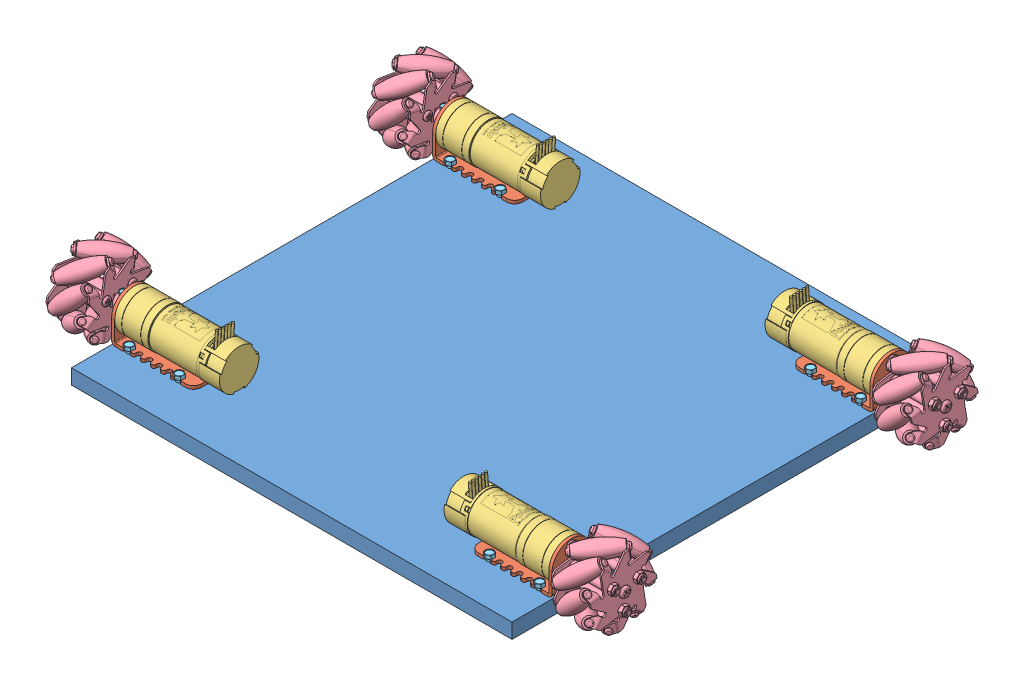
SolidWorks assembly Motor_Wheel_Assembly2, configuration Default. Lengths in mm.
Overall size (353.35 66.93 279.4).
37 component instances, 5 part files, 44 mates.
Components (placement in the parent):
- motor_Mount_plate-1: motor_Mount_plate [Default] at (148.2715 106.099 214.9972) size (279.4 9.53 279.4)
- Motor_Wheel_Assembly-1: Motor_Wheel_Assembly [Default] at (61.3699 101.7509 295.5817) x (0 0 1) z (-1 0 0) size (66.93 66.93 105.45)
  - pololu-25d-mm-metal-gearmotor-bracket.step-1: pololu-25d-mm-metal-gearmotor-bracket.step [Default] at (22.2155 27.3731 38.2734) size (25 27 52)
  - 25d-metal-gearmotor-34-47-encoder.step-1: 25d-metal-gearmotor-34-47-encoder.step [Default] at (21.2155 28.3731 50.7734) size (25 30.75 78.95)
  - 48MM Steel Mecanum Wheel2-1: 48MM Steel Mecanum Wheel2 [Default] at (-15.358 23.7538 36.4991) x (0 0 1) z (0.578972 0.815347 0) size (35.5 48 48)
  - hex screw_am-1: hex screw_am [B18.6.7M - M2.5 x 0.45 x 3 Indented HHMS --3N] at (21.4481 34.8545 57.659) x (-0.070518 -0.997511 -0.000043) z (-0.2808 0.019809 0.959562) size (5.1 4.62 4)
- Motor_Wheel_Assembly-2: Motor_Wheel_Assembly [Default] at (61.3699 101.7509 91.9817) x (0 0 1) z (-1 0 0) size (66.93 66.93 105.45)
  - pololu-25d-mm-metal-gearmotor-bracket.step-1: pololu-25d-mm-metal-gearmotor-bracket.step [Default] at (22.2155 27.3731 38.2734) size (25 27 52)
  - 25d-metal-gearmotor-34-47-encoder.step-1: 25d-metal-gearmotor-34-47-encoder.step [Default] at (21.2155 28.3731 50.7734) size (25 30.75 78.95)
  - 48MM Steel Mecanum Wheel2-1: 48MM Steel Mecanum Wheel2 [Default] at (-15.358 23.7538 36.4991) x (0 0 1) z (0.578972 0.815347 0) size (35.5 48 48)
  - hex screw_am-1: hex screw_am [B18.6.7M - M2.5 x 0.45 x 3 Indented HHMS --3N] at (21.4481 34.8545 57.659) x (-0.070518 -0.997511 -0.000043) z (-0.2808 0.019809 0.959562) size (5.1 4.62 4)
- Motor_Wheel_Assembly-3: Motor_Wheel_Assembly [Default] at (235.1732 101.7509 134.4127) x (0 0 -1) z (1 0 0) size (66.93 66.93 105.45)
  - pololu-25d-mm-metal-gearmotor-bracket.step-1: pololu-25d-mm-metal-gearmotor-bracket.step [Default] at (22.2155 27.3731 38.2734) size (25 27 52)
  - 25d-metal-gearmotor-34-47-encoder.step-1: 25d-metal-gearmotor-34-47-encoder.step [Default] at (21.2155 28.3731 50.7734) size (25 30.75 78.95)
  - 48MM Steel Mecanum Wheel2-1: 48MM Steel Mecanum Wheel2 [Default] at (-15.358 23.7538 36.4991) x (0 0 1) z (0.578972 0.815347 0) size (35.5 48 48)
  - hex screw_am-1: hex screw_am [B18.6.7M - M2.5 x 0.45 x 3 Indented HHMS --3N] at (21.4481 34.8545 57.659) x (-0.070518 -0.997511 -0.000043) z (-0.2808 0.019809 0.959562) size (5.1 4.62 4)
- Motor_Wheel_Assembly-4: Motor_Wheel_Assembly [Default] at (235.1732 101.7509 338.0127) x (0 0 -1) z (1 0 0) size (66.93 66.93 105.45)
  - pololu-25d-mm-metal-gearmotor-bracket.step-1: pololu-25d-mm-metal-gearmotor-bracket.step [Default] at (22.2155 27.3731 38.2734) size (25 27 52)
  - 25d-metal-gearmotor-34-47-encoder.step-1: 25d-metal-gearmotor-34-47-encoder.step [Default] at (21.2155 28.3731 50.7734) size (25 30.75 78.95)
  - 48MM Steel Mecanum Wheel2-1: 48MM Steel Mecanum Wheel2 [Default] at (-15.358 23.7538 36.4991) x (0 0 1) z (0.578972 0.815347 0) size (35.5 48 48)
  - hex screw_am-1: hex screw_am [B18.6.7M - M2.5 x 0.45 x 3 Indented HHMS --3N] at (21.4481 34.8545 57.659) x (-0.070518 -0.997511 -0.000043) z (-0.2808 0.019809 0.959562) size (5.1 4.62 4)
- hex screw_am-2: hex screw_am [B18.6.7M - M3 x 0.5 x 8 Indented HHMS --8N] at (278.4215 119.924 327.6472) x (0 -1 0) z (-0.546944 0 0.837169) size (10.3 5.77 5)
- hex screw_am-3: hex screw_am [B18.6.7M - M3 x 0.5 x 8 Indented HHMS --8N] at (18.1215 119.924 327.6472) x (0 -1 0) z (-0.546944 0 0.837169) size (10.3 5.77 5)
- hex screw_am-4: hex screw_am [B18.6.7M - M3 x 0.5 x 8 Indented HHMS --8N] at (18.1215 119.924 305.9472) x (0 -1 0) z (-0.546944 0 0.837169) size (10.3 5.77 5)
- hex screw_am-5: hex screw_am [B18.6.7M - M3 x 0.5 x 8 Indented HHMS --8N] at (49.8515 119.924 305.9472) x (0 -1 0) z (-0.546944 0 0.837169) size (10.3 5.77 5)
- hex screw_am-6: hex screw_am [B18.6.7M - M3 x 0.5 x 8 Indented HHMS --8N] at (18.1215 119.924 102.3472) x (0 -1 0) z (-0.546944 0 0.837169) size (10.3 5.77 5)
- hex screw_am-7: hex screw_am [B18.6.7M - M3 x 0.5 x 8 Indented HHMS --8N] at (18.1215 119.924 124.0472) x (0 -1 0) z (-0.546944 0 0.837169) size (10.3 5.77 5)
- hex screw_am-8: hex screw_am [B18.6.7M - M3 x 0.5 x 8 Indented HHMS --8N] at (49.8515 119.924 124.0472) x (0 -1 0) z (-0.546944 0 0.837169) size (10.3 5.77 5)
- hex screw_am-9: hex screw_am [B18.6.7M - M3 x 0.5 x 8 Indented HHMS --8N] at (278.4215 119.924 305.9472) x (0 -1 0) z (0 0 1) size (10.3 5.77 5)
- hex screw_am-10: hex screw_am [B18.6.7M - M3 x 0.5 x 8 Indented HHMS --8N] at (49.8515 119.924 327.6472) x (0 -1 0) z (-0.546944 0 0.837169) size (10.3 5.77 5)
- hex screw_am-11: hex screw_am [B18.6.7M - M3 x 0.5 x 8 Indented HHMS --8N] at (246.6915 119.924 327.6472) x (0 -1 0) z (-0.546944 0 0.837169) size (10.3 5.77 5)
- hex screw_am-12: hex screw_am [B18.6.7M - M3 x 0.5 x 8 Indented HHMS --8N] at (246.6915 119.924 305.9472) x (0 -1 0) z (-0.546944 0 0.837169) size (10.3 5.77 5)
- hex screw_am-13: hex screw_am [B18.6.7M - M3 x 0.5 x 8 Indented HHMS --8N] at (49.8515 119.924 102.3472) x (0 -1 0) z (-0.546944 0 0.837169) size (10.3 5.77 5)
- hex screw_am-14: hex screw_am [B18.6.7M - M3 x 0.5 x 8 Indented HHMS --8N] at (278.4215 119.924 102.3472) x (0 -1 0) z (-0.546944 0 0.837169) size (10.3 5.77 5)
- hex screw_am-15: hex screw_am [B18.6.7M - M3 x 0.5 x 8 Indented HHMS --8N] at (246.6915 119.924 124.0472) x (0 -1 0) z (-0.546944 0 0.837169) size (10.3 5.77 5)
- hex screw_am-16: hex screw_am [B18.6.7M - M3 x 0.5 x 8 Indented HHMS --8N] at (246.6915 119.924 102.3472) x (0 -1 0) z (-0.546944 0 0.837169) size (10.3 5.77 5)
- hex screw_am-17: hex screw_am [B18.6.7M - M3 x 0.5 x 8 Indented HHMS --8N] at (278.4215 119.924 124.0472) x (0 -1 0) z (-0.546944 0 0.837169) size (10.3 5.77 5)
Mates (geometry in assembly coordinates):
- Coincident1: coincident anti-aligned: plane of motor_Mount_plate-1 through (148.2715 115.624 214.9972) normal (0 1 0); plane of Motor_Wheel_Assembly-4/pololu-25d-mm-metal-gearmotor-bracket.step-1 through (285.9465 115.624 304.2972) normal (0 -1 0)
- Concentric1: concentric aligned: cylinder of motor_Mount_plate-1 through (278.4215 115.624 305.9472) axis (0 1 0) radius 1.65; cylinder of Motor_Wheel_Assembly-4/pololu-25d-mm-metal-gearmotor-bracket.step-1 through (278.4215 115.624 305.9472) axis (0 1 0) radius 1.65
- Parallel1: parallel aligned: plane of motor_Mount_plate-1 through (287.9715 115.624 75.2972) normal (1 0 0); plane of Motor_Wheel_Assembly-4/pololu-25d-mm-metal-gearmotor-bracket.step-1 through (287.9465 117.624 304.2972) normal (1 0 0)
- Coincident3: coincident anti-aligned: plane of motor_Mount_plate-1 through (148.2715 115.624 214.9972) normal (0 1 0); plane of Motor_Wheel_Assembly-3/pololu-25d-mm-metal-gearmotor-bracket.step-1 through (285.9465 115.624 100.6972) normal (0 -1 0)
- Concentric2: concentric aligned: cylinder of motor_Mount_plate-1 through (278.4215 115.624 102.3472) axis (0 1 0) radius 1.65; cylinder of Motor_Wheel_Assembly-3/pololu-25d-mm-metal-gearmotor-bracket.step-1 through (278.4215 115.624 102.3472) axis (0 1 0) radius 1.65
- Parallel3: parallel aligned: plane of motor_Mount_plate-1 through (287.9715 115.624 75.2972) normal (1 0 0); plane of Motor_Wheel_Assembly-3/pololu-25d-mm-metal-gearmotor-bracket.step-1 through (287.9465 117.624 100.6972) normal (1 0 0)
- Coincident6: coincident anti-aligned: plane of motor_Mount_plate-1 through (148.2715 115.624 214.9972) normal (0 1 0); plane of Motor_Wheel_Assembly-2/pololu-25d-mm-metal-gearmotor-bracket.step-1 through (10.5965 115.624 125.6972) normal (0 -1 0)
- Concentric3: concentric aligned: cylinder of motor_Mount_plate-1 through (18.1215 115.624 124.0472) axis (0 1 0) radius 1.65; cylinder of Motor_Wheel_Assembly-2/pololu-25d-mm-metal-gearmotor-bracket.step-1 through (18.1215 115.624 124.0472) axis (0 1 0) radius 1.65
- Parallel4: parallel aligned: plane of motor_Mount_plate-1 through (8.5715 115.624 75.2972) normal (-1 0 0); plane of Motor_Wheel_Assembly-2/pololu-25d-mm-metal-gearmotor-bracket.step-1 through (8.5965 117.624 125.6972) normal (-1 0 0)
- Coincident8: coincident anti-aligned: plane of motor_Mount_plate-1 through (148.2715 115.624 214.9972) normal (0 1 0); plane of Motor_Wheel_Assembly-1/pololu-25d-mm-metal-gearmotor-bracket.step-1 through (10.5965 115.624 329.2972) normal (0 -1 0)
- Concentric4: concentric aligned: cylinder of motor_Mount_plate-1 through (18.1215 115.624 305.9472) axis (0 1 0) radius 1.65; cylinder of Motor_Wheel_Assembly-1/pololu-25d-mm-metal-gearmotor-bracket.step-1 through (18.1215 115.624 305.9472) axis (0 1 0) radius 1.65
- Parallel5: parallel aligned: plane of motor_Mount_plate-1 through (8.5715 115.624 75.2972) normal (-1 0 0); plane of Motor_Wheel_Assembly-1/pololu-25d-mm-metal-gearmotor-bracket.step-1 through (8.5965 117.624 329.2972) normal (-1 0 0)
- Concentric6: concentric aligned: cylinder of motor_Mount_plate-1 through (18.1215 115.624 327.6472) axis (0 1 0) radius 1.65; cylinder of hex screw_am-3 through (18.1215 145.324 327.6472) axis (0 1 0) radius 1.5
- Coincident9: coincident anti-aligned: plane of Motor_Wheel_Assembly-1/pololu-25d-mm-metal-gearmotor-bracket.step-1 through (10.5965 117.624 329.2972) normal (0 1 0); plane of hex screw_am-3 through (19.3773 117.624 328.4676) normal (0 -1 0)
- Concentric7: concentric aligned: cylinder of motor_Mount_plate-1 through (49.8515 115.624 327.6472) axis (0 1 0) radius 1.65; cylinder of hex screw_am-10 through (49.8515 145.324 327.6472) axis (0 1 0) radius 1.5
- Coincident10: coincident anti-aligned: plane of Motor_Wheel_Assembly-1/pololu-25d-mm-metal-gearmotor-bracket.step-1 through (10.5965 117.624 329.2972) normal (0 1 0); plane of hex screw_am-10 through (51.1073 117.624 328.4676) normal (0 -1 0)
- Concentric8: concentric aligned: cylinder of motor_Mount_plate-1 through (246.6915 115.624 327.6472) axis (0 1 0) radius 1.65; cylinder of hex screw_am-11 through (246.6915 145.324 327.6472) axis (0 1 0) radius 1.5
- Coincident11: coincident anti-aligned: plane of Motor_Wheel_Assembly-4/pololu-25d-mm-metal-gearmotor-bracket.step-1 through (285.9465 117.624 304.2972) normal (0 1 0); plane of hex screw_am-11 through (247.9473 117.624 328.4676) normal (0 -1 0)
- Concentric9: concentric aligned: cylinder of motor_Mount_plate-1 through (278.4215 115.624 327.6472) axis (0 1 0) radius 1.65; cylinder of hex screw_am-2 through (278.4215 145.324 327.6472) axis (0 1 0) radius 1.5
- Coincident12: coincident anti-aligned: plane of Motor_Wheel_Assembly-4/pololu-25d-mm-metal-gearmotor-bracket.step-1 through (285.9465 117.624 304.2972) normal (0 1 0); plane of hex screw_am-2 through (279.6773 117.624 328.4676) normal (0 -1 0)
- Concentric10: concentric aligned: cylinder of motor_Mount_plate-1 through (246.6915 115.624 305.9472) axis (0 1 0) radius 1.65; cylinder of hex screw_am-12 through (246.6915 145.324 305.9472) axis (0 1 0) radius 1.5
- Coincident13: coincident anti-aligned: plane of Motor_Wheel_Assembly-4/pololu-25d-mm-metal-gearmotor-bracket.step-1 through (285.9465 117.624 304.2972) normal (0 1 0); plane of hex screw_am-12 through (247.9473 117.624 306.7676) normal (0 -1 0)
- Coincident14: coincident anti-aligned: plane of Motor_Wheel_Assembly-4/pololu-25d-mm-metal-gearmotor-bracket.step-1 through (285.9465 117.624 304.2972) normal (0 1 0); plane of hex screw_am-9 through (279.9215 117.624 305.9472) normal (0 -1 0)
- Concentric11: concentric aligned: cylinder of motor_Mount_plate-1 through (278.4215 115.624 305.9472) axis (0 1 0) radius 1.65; cylinder of hex screw_am-9 through (278.4215 145.324 305.9472) axis (0 1 0) radius 1.5
- Concentric12: concentric aligned: cylinder of motor_Mount_plate-1 through (278.4215 115.624 102.3472) axis (0 1 0) radius 1.65; cylinder of hex screw_am-14 through (278.4215 145.324 102.3472) axis (0 1 0) radius 1.5
- Coincident15: coincident anti-aligned: plane of Motor_Wheel_Assembly-3/pololu-25d-mm-metal-gearmotor-bracket.step-1 through (285.9465 117.624 100.6972) normal (0 1 0); plane of hex screw_am-14 through (279.6773 117.624 103.1676) normal (0 -1 0)
- Concentric13: concentric aligned: cylinder of motor_Mount_plate-1 through (246.6915 115.624 102.3472) axis (0 1 0) radius 1.65; cylinder of hex screw_am-16 through (246.6915 145.324 102.3472) axis (0 1 0) radius 1.5
- Coincident16: coincident anti-aligned: plane of Motor_Wheel_Assembly-3/pololu-25d-mm-metal-gearmotor-bracket.step-1 through (285.9465 117.624 100.6972) normal (0 1 0); plane of hex screw_am-16 through (247.9473 117.624 103.1676) normal (0 -1 0)
- Concentric14: concentric aligned: cylinder of motor_Mount_plate-1 through (49.8515 115.624 102.3472) axis (0 1 0) radius 1.65; cylinder of hex screw_am-13 through (49.8515 145.324 102.3472) axis (0 1 0) radius 1.5
- Coincident17: coincident anti-aligned: plane of Motor_Wheel_Assembly-2/pololu-25d-mm-metal-gearmotor-bracket.step-1 through (10.5965 117.624 125.6972) normal (0 1 0); plane of hex screw_am-13 through (51.1073 117.624 103.1676) normal (0 -1 0)
- Concentric15: concentric aligned: cylinder of motor_Mount_plate-1 through (18.1215 115.624 102.3472) axis (0 1 0) radius 1.65; cylinder of hex screw_am-6 through (18.1215 145.324 102.3472) axis (0 1 0) radius 1.5
- Coincident18: coincident anti-aligned: plane of Motor_Wheel_Assembly-2/pololu-25d-mm-metal-gearmotor-bracket.step-1 through (10.5965 117.624 125.6972) normal (0 1 0); plane of hex screw_am-6 through (19.3773 117.624 103.1676) normal (0 -1 0)
- Concentric16: concentric aligned: cylinder of motor_Mount_plate-1 through (18.1215 115.624 124.0472) axis (0 1 0) radius 1.65; cylinder of hex screw_am-7 through (18.1215 145.324 124.0472) axis (0 1 0) radius 1.5
- Coincident19: coincident anti-aligned: plane of Motor_Wheel_Assembly-2/pololu-25d-mm-metal-gearmotor-bracket.step-1 through (10.5965 117.624 125.6972) normal (0 1 0); plane of hex screw_am-7 through (19.3773 117.624 124.8676) normal (0 -1 0)
- Concentric17: concentric aligned: cylinder of motor_Mount_plate-1 through (49.8515 115.624 124.0472) axis (0 1 0) radius 1.65; cylinder of hex screw_am-8 through (49.8515 145.324 124.0472) axis (0 1 0) radius 1.5
- Coincident20: coincident anti-aligned: plane of Motor_Wheel_Assembly-2/pololu-25d-mm-metal-gearmotor-bracket.step-1 through (10.5965 117.624 125.6972) normal (0 1 0); plane of hex screw_am-8 through (51.1073 117.624 124.8676) normal (0 -1 0)
- Concentric18: concentric aligned: cylinder of motor_Mount_plate-1 through (49.8515 115.624 305.9472) axis (0 1 0) radius 1.65; cylinder of hex screw_am-5 through (49.8515 145.324 305.9472) axis (0 1 0) radius 1.5
- Coincident21: coincident anti-aligned: plane of Motor_Wheel_Assembly-1/pololu-25d-mm-metal-gearmotor-bracket.step-1 through (10.5965 117.624 329.2972) normal (0 1 0); plane of hex screw_am-5 through (51.1073 117.624 306.7676) normal (0 -1 0)
- Concentric19: concentric aligned: cylinder of motor_Mount_plate-1 through (18.1215 115.624 305.9472) axis (0 1 0) radius 1.65; cylinder of hex screw_am-4 through (18.1215 145.324 305.9472) axis (0 1 0) radius 1.5
- Coincident22: coincident anti-aligned: plane of Motor_Wheel_Assembly-1/pololu-25d-mm-metal-gearmotor-bracket.step-1 through (10.5965 117.624 329.2972) normal (0 1 0); plane of hex screw_am-4 through (19.3773 117.624 306.7676) normal (0 -1 0)
- Concentric20: concentric aligned: cylinder of motor_Mount_plate-1 through (246.6915 115.624 124.0472) axis (0 1 0) radius 1.65; cylinder of hex screw_am-15 through (246.6915 145.324 124.0472) axis (0 1 0) radius 1.5
- Coincident24: coincident anti-aligned: plane of Motor_Wheel_Assembly-3/pololu-25d-mm-metal-gearmotor-bracket.step-1 through (285.9465 117.624 100.6972) normal (0 1 0); plane of hex screw_am-15 through (247.9473 117.624 124.8676) normal (0 -1 0)
- Concentric21: concentric: cylinder of motor_Mount_plate-1 through (278.4215 115.624 124.0472) axis (0 1 0) radius 1.65; cylinder of hex screw_am-17 through (278.4215 145.324 124.0472) axis (0 1 0) radius 1.5
- Coincident25: coincident anti-aligned: plane of Motor_Wheel_Assembly-3/pololu-25d-mm-metal-gearmotor-bracket.step-1 through (285.9465 117.624 100.6972) normal (0 1 0); plane of hex screw_am-17 through (279.6773 117.624 124.8676) normal (0 -1 0)
